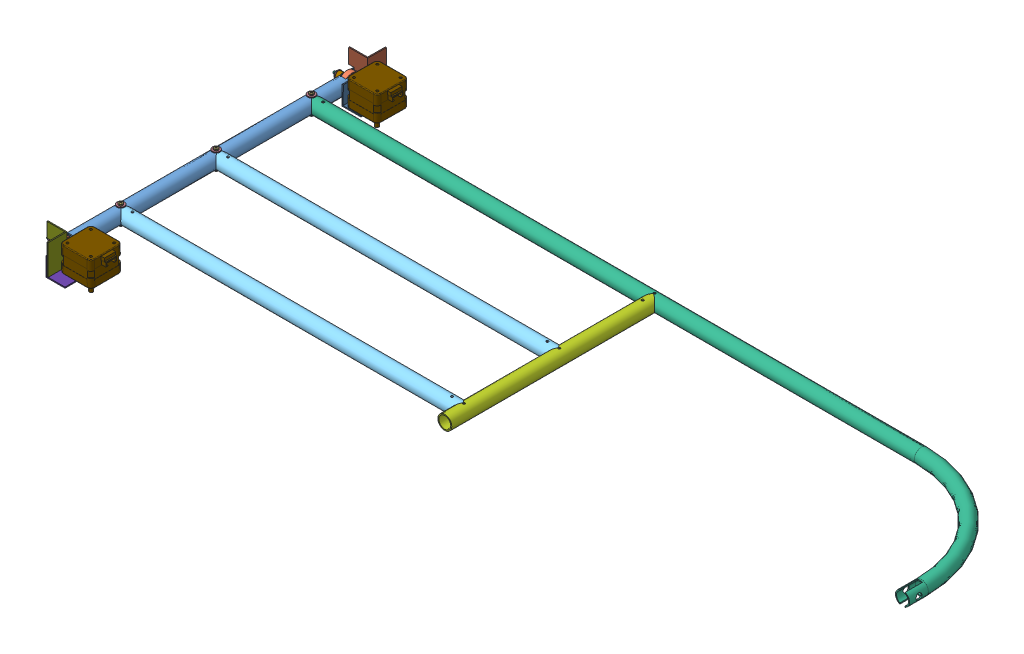
SolidWorks assembly planb, configuration Default. Lengths in mm.
Overall size (995.09 62.65 450.66).
49 component instances, 18 part files, 101 mates.
Components (placement in the parent):
- fr_0001-1: fr_0001 [Default] at (6.245 11.5979 -203.2) size (18.72 18.72 406.4)
- bearing_0006-1: bearing_0006 [Default] at (9.7384 11.5979 190.5) x (0 0.62992 0.77666) z (-1 0 0) size (22 22 7.01)
- bearing_0006-2: bearing_0006 [Default] at (9.6944 11.5979 -190.5) x (0 -0.257155 0.96637) z (-1 0 0) size (22 22 7.01)
- fr_0006-1: fr_0006 [Default] at (6.245 11.5979 127) x (-1 0 0) z (0 0 -1) size (15.98 15.98 25.4)
- fr_0006-2: fr_0006 [Default] at (6.245 11.5979 -25.4) size (15.98 15.98 25.4)
- fr_0006-3: fr_0006 [Default] at (6.245 11.5979 -152.4) size (15.98 15.98 25.4)
- fr_0007-1: fr_0007 [Default] at (2.92 11.5979 114.3) x (0 0 -1) z (1 0 0) size (15.85 15.85 25.4)
- fr_0007-2: fr_0007 [Default] at (2.92 11.5979 -12.7) x (0 0 -1) z (1 0 0) size (15.85 15.85 25.4)
- fr_0007-3: fr_0007 [Default] at (2.92 11.5979 -139.7) x (0 0 -1) z (1 0 0) size (15.85 15.85 25.4)
- fr_0002-1: fr_0002 [Default] at (463.3 11.5979 114.3) x (0 0 -1) z (-1 0 0) size (18.72 18.72 455.37)
- fr_0002-2: fr_0002 [Default] at (6.09 11.5979 -12.7) x (0 0 -1) z (1 0 0) size (18.72 18.72 455.37)
- fr_0003-1: fr_0003 [Default] at (6.09 11.5979 -139.7) x (0 0 1) z (1 0 0) size (186.76 18.72 973.3)
- fr_0004-1: fr_0004 [Default] at (463.145 11.5979 -139.7) size (18.72 18.72 278.48)
- fr_0006-4: fr_0006 [Default] at (463.145 11.5979 101.6) size (15.98 15.98 25.4)
- fr_0006-5: fr_0006 [Default] at (463.145 11.5979 -25.4) size (15.98 15.98 25.4)
- fr_0006-6: fr_0006 [Default] at (450.445 11.5979 -139.7) x (0 0 1) z (1 0 0) size (15.98 15.98 25.4)
- fr_0007-4: fr_0007 [Default] at (466.47 11.5979 114.3) x (0 0 1) z (-1 0 0) size (15.85 15.85 25.4)
- fr_0007-5: fr_0007 [Default] at (466.47 11.5979 -12.7) x (0 0 1) z (-1 0 0) size (15.85 15.85 25.4)
- fr_0007-6: fr_0007 [Default] at (463.145 11.5979 -143.025) size (15.85 15.85 25.4)
- fr_0008-1: fr_0008 [Default] at (17.685 11.5979 -190.5) x (0 0.959946 -0.280186) z (-1 0 0) size (9.4 9.4 26)
- fr_0009-1: fr_0009 [Default] at (-8.315 11.5979 -190.5) x (0 0 -1) z (1 0 0) size (9.4 9.4 5)
- fr_0010-1: fr_0010 [Default] at (17.685 23.8614 -225.2243) x (1 0 0) z (0 0.009997 0.99995) size (25.22 25.22 56)
- fr_0011-1: fr_0011 [Default] at (20.525 40.0606 -225.3863) x (-1 0 0) z (0 -0.99995 0.009997) size (25.22 25.22 40)
- B18.6.7M - M3 x 0.5 x 25 Type I Cross Recessed PHMS --25N-1: B18.6.7M - M3 x 0.5 x 25 Type I Cross Recessed PHMS --25N [Default] at (6.245 24.5579 114.3) x (0 -1 0) z (0 0 1) size (27.37 5.6 5.6)
- B18.22M - Plain washer, 3 mm, regular-1: B18.22M - Plain washer, 3 mm, regular [Default] at (6.245 2.2379 114.3) x (0 1 0) z (0 0 1) size (1.2 10 10)
- B18.22M - Plain washer, 3 mm, regular-2: B18.22M - Plain washer, 3 mm, regular [Default] at (6.245 20.9579 114.3) x (0 -1 0) z (0 0 1) size (1.2 10 10)
- B18.2.4.1M - Hex nut, Style 1,  M3 x 0.5 --D-N-1: B18.2.4.1M - Hex nut, Style 1,  M3 x 0.5 --D-N [Default] at (6.245 -1.3621 114.3) x (1 0 0) z (0 -1 0) size (5.5 6.35 2.4)
- B18.6.7M - M3 x 0.5 x 25 Type I Cross Recessed PHMS --25N-2: B18.6.7M - M3 x 0.5 x 25 Type I Cross Recessed PHMS --25N [Default] at (6.245 24.5579 -12.7) x (0 -1 0) z (0 0 1) size (27.37 5.6 5.6)
- B18.6.7M - M3 x 0.5 x 25 Type I Cross Recessed PHMS --25N-3: B18.6.7M - M3 x 0.5 x 25 Type I Cross Recessed PHMS --25N [Default] at (6.245 24.5579 -139.7) x (0 -1 0) z (0 0 1) size (27.37 5.6 5.6)
- B18.22M - Plain washer, 3 mm, regular-3: B18.22M - Plain washer, 3 mm, regular [Default] at (6.245 20.9579 -139.7) x (0 -1 0) z (0 0 1) size (1.2 10 10)
- B18.22M - Plain washer, 3 mm, regular-4: B18.22M - Plain washer, 3 mm, regular [Default] at (19.105 11.5979 -190.5) x (-1 0 0) z (0 0 1) size (1.2 10 10)
- B18.2.4.1M - Hex nut, Style 1,  M3 x 0.5 --D-N-2: B18.2.4.1M - Hex nut, Style 1,  M3 x 0.5 --D-N [Default] at (6.245 -1.3621 -139.7) x (1 0 0) z (0 -1 0) size (5.5 6.35 2.4)
- B18.2.4.1M - Hex nut, Style 1,  M3 x 0.5 --D-N-3: B18.2.4.1M - Hex nut, Style 1,  M3 x 0.5 --D-N [Default] at (6.245 -1.3621 -12.7) x (1 0 0) z (0 -1 0) size (5.5 6.35 2.4)
- B18.6.7M - M3 x 0.5 x 35 Type I Cross Recessed PHMS --35N-1: B18.6.7M - M3 x 0.5 x 35 Type I Cross Recessed PHMS --35N [Default] at (22.705 11.5979 -190.5) x (-1 0 0) z (0 0 1) size (37.37 5.6 5.6)
- B18.22M - Plain washer, 3 mm, regular-5: B18.22M - Plain washer, 3 mm, regular [Default] at (6.245 20.9579 -12.7) x (0 -1 0) z (0 0 1) size (1.2 10 10)
- B18.2.4.1M - Hex nut, Style 1,  M3 x 0.5 --D-N-4: B18.2.4.1M - Hex nut, Style 1,  M3 x 0.5 --D-N [Default] at (-9.515 11.5979 -190.5) x (0 0.99994 0.010936) z (1 0 0) size (5.5 6.35 2.4)
- B18.22M - Plain washer, 3 mm, regular-6: B18.22M - Plain washer, 3 mm, regular [Default] at (6.245 2.2379 -139.7) x (0 1 0) z (0 0 1) size (1.2 10 10)
- B18.22M - Plain washer, 3 mm, regular-7: B18.22M - Plain washer, 3 mm, regular [Default] at (-8.315 11.5979 -190.5) size (1.2 10 10)
- B18.22M - Plain washer, 3 mm, regular-8: B18.22M - Plain washer, 3 mm, regular [Default] at (6.245 2.2379 -12.7) x (0 1 0) z (0 0 1) size (1.2 10 10)
- fr_0014-1: fr_0014 [Default] at (20.445 0.1994 225.0319) x (-1 0 0) z (0 0.999982 0.006033) size (25.22 25.22 40)
- fr_0012-1: fr_0012 [Default] at (17.605 24.3368 169.1765) x (1 0 0) z (0 -0.006033 0.999982) size (25.22 25.22 56)
- fr_0008-2: fr_0008 [Default] at (17.605 11.5979 190.5) x (0 0.963539 -0.267568) z (-1 0 0) size (9.4 9.4 26)
- fr_0009-2: fr_0009 [Default] at (-8.395 11.5979 190.5) x (0 -0.963539 0.267568) z (1 0 0) size (9.4 9.4 5)
- B18.6.7M - M3 x 0.5 x 35 Type I Cross Recessed PHMS --35N-2: B18.6.7M - M3 x 0.5 x 35 Type I Cross Recessed PHMS --35N [Default] at (22.625 11.5979 190.5) x (-1 0 0) z (0 0.963539 -0.267568) size (37.37 5.6 5.6)
- B18.2.4.1M - Hex nut, Style 1,  M3 x 0.5 --D-N-5: B18.2.4.1M - Hex nut, Style 1,  M3 x 0.5 --D-N [Default] at (-9.595 11.5979 190.5) x (0 0.963539 -0.267568) z (1 0 0) size (5.5 6.35 2.4)
- B18.22M - Plain washer, 3 mm, regular-9: B18.22M - Plain washer, 3 mm, regular [Default] at (-9.595 11.5979 190.5) x (-1 0 0) z (0 0.963539 -0.267568) size (1.2 10 10)
- B18.22M - Plain washer, 3 mm, regular-10: B18.22M - Plain washer, 3 mm, regular [Default] at (19.025 11.5979 190.5) x (-1 0 0) z (0 0.963539 -0.267568) size (1.2 10 10)
- SW3dPS-037-1: SW3dPS-037 [Default] at (42.825 0.4081 190.4325) x (0 0.999982 0.006033) z (0 -0.006033 0.999982) size (56.01 48 42)
- SW3dPS-037-2: SW3dPS-037 [Default] at (42.905 0.4085 -190.3881) x (0 0.99995 -0.009997) z (0 0.009997 0.99995) size (56.01 48 42)
Mates (geometry in assembly coordinates):
- Concentric2: concentric aligned: cylinder of fr_0001-1 through (6.245 11.5979 203.2) axis (0 0 -1) radius 9.36; circle of fr_0006-1
- Concentric5: concentric aligned: cylinder of fr_0001-1 through (15.605 11.5979 114.3) axis (-1 0 0) radius 3.5; cylinder of fr_0006-1 through (14.235 11.5979 114.3) axis (-1 0 0) radius 3.5
- Concentric6: concentric anti-aligned: cylinder of fr_0001-1 through (6.245 11.5979 203.2) axis (0 0 -1) radius 9.36; circle of fr_0006-2
- Concentric7: concentric anti-aligned: cylinder of fr_0001-1 through (15.605 11.5979 -12.7) axis (-1 0 0) radius 3.5; cylinder of fr_0006-2 through (-1.745 11.5979 -12.7) axis (1 0 0) radius 3.5
- Concentric8: concentric anti-aligned: cylinder of fr_0001-1 through (6.245 11.5979 203.2) axis (0 0 -1) radius 9.36; circle of fr_0006-3
- Concentric9: concentric anti-aligned: cylinder of fr_0001-1 through (15.605 11.5979 -139.7) axis (-1 0 0) radius 3.5; cylinder of fr_0006-3 through (-1.745 11.5979 -139.7) axis (1 0 0) radius 3.5
- Concentric11: concentric aligned: cylinder of fr_0006-1 through (14.235 11.5979 114.3) axis (-1 0 0) radius 3.5; cylinder of fr_0007-1 through (15.67 11.5979 114.3) axis (-1 0 0) radius 3.48
- Concentric12: concentric aligned: cylinder of fr_0006-1 through (6.245 3.6079 114.3) axis (0 1 0) radius 1.55; cylinder of fr_0007-1 through (6.245 3.6729 114.3) axis (0 1 0) radius 1.55
- Concentric13: concentric anti-aligned: cylinder of fr_0006-2 through (-1.745 11.5979 -12.7) axis (1 0 0) radius 3.5; cylinder of fr_0007-2 through (15.67 11.5979 -12.7) axis (-1 0 0) radius 3.48
- Concentric14: concentric aligned: cylinder of fr_0006-2 through (6.245 3.6079 -12.7) axis (0 1 0) radius 1.55; cylinder of fr_0007-2 through (6.245 3.6729 -12.7) axis (0 1 0) radius 1.55
- Concentric15: concentric anti-aligned: cylinder of fr_0006-3 through (-1.745 11.5979 -139.7) axis (1 0 0) radius 3.5; cylinder of fr_0007-3 through (15.67 11.5979 -139.7) axis (-1 0 0) radius 3.48
- Concentric16: concentric aligned: cylinder of fr_0006-3 through (6.245 3.6079 -139.7) axis (0 1 0) radius 1.55; cylinder of fr_0007-3 through (6.245 3.6729 -139.7) axis (0 1 0) radius 1.55
- Concentric17: concentric aligned: cylinder of fr_0001-1 through (15.605 11.5979 -190.5) axis (-1 0 0) radius 4; cylinder of bearing_0006-2 through (-9.3056 11.5979 -190.5) axis (-1 0 0) radius 4
- Concentric18: concentric anti-aligned: cylinder of fr_0001-1 through (-3.115 11.5979 190.5) axis (1 0 0) radius 4; cylinder of bearing_0006-1 through (-9.2616 11.5979 190.5) axis (-1 0 0) radius 4
- Concentric19: concentric anti-aligned: cylinder of fr_0007-1 through (28.32 11.5979 114.3) axis (-1 0 0) radius 7.925; cylinder of fr_0002-1 through (6.1 11.5979 114.3) axis (1 0 0) radius 9.36
- Parallel1: parallel anti-aligned: cylinder of fr_0007-1 through (21.97 3.6729 114.3) axis (0 1 0) radius 1.55; cylinder of fr_0002-1 through (21.97 20.9579 114.3) axis (0 -1 0) radius 1.55
- Concentric20: concentric anti-aligned: cylinder of fr_0007-1 through (21.97 3.6729 114.3) axis (0 1 0) radius 1.55; cylinder of fr_0002-1 through (21.97 20.9579 114.3) axis (0 -1 0) radius 1.55
- Concentric21: concentric aligned: cylinder of fr_0007-2 through (28.32 11.5979 -12.7) axis (-1 0 0) radius 7.925; cylinder of fr_0002-2 through (463.29 11.5979 -12.7) axis (-1 0 0) radius 9.36
- Concentric22: concentric aligned: cylinder of fr_0007-2 through (21.97 3.6729 -12.7) axis (0 1 0) radius 1.55; cylinder of fr_0002-2 through (21.97 2.2379 -12.7) axis (0 1 0) radius 1.55
- Concentric23: concentric aligned: cylinder of fr_0007-3 through (28.32 11.5979 -139.7) axis (-1 0 0) radius 7.925; cylinder of fr_0003-1 through (818.29 11.5979 -139.7) axis (-1 0 0) radius 7.99
- Concentric24: concentric anti-aligned: cylinder of fr_0007-3 through (21.97 3.6729 -139.7) axis (0 1 0) radius 1.55; cylinder of fr_0003-1 through (21.97 20.9579 -139.7) axis (0 -1 0) radius 1.55
- Concentric25: concentric anti-aligned: cylinder of fr_0002-1 through (6.1 11.5979 114.3) axis (1 0 0) radius 7.99; circle of fr_0007-4
- Concentric26: concentric anti-aligned: cylinder of fr_0002-1 through (447.42 20.9579 114.3) axis (0 -1 0) radius 1.55; cylinder of fr_0007-4 through (447.42 3.6729 114.3) axis (0 1 0) radius 1.55
- Concentric27: concentric anti-aligned: cylinder of fr_0002-2 through (463.29 11.5979 -12.7) axis (-1 0 0) radius 7.99; cylinder of fr_0007-5 through (441.07 11.5979 -12.7) axis (1 0 0) radius 7.925
- Concentric28: concentric aligned: cylinder of fr_0002-2 through (447.42 2.2379 -12.7) axis (0 1 0) radius 1.55; cylinder of fr_0007-5 through (447.42 3.6729 -12.7) axis (0 1 0) radius 1.55
- Concentric29: concentric anti-aligned: cylinder of fr_0004-1 through (463.145 11.5979 139.7) axis (0 0 -1) radius 7.99; circle of fr_0006-5
- Concentric30: concentric aligned: cylinder of fr_0004-1 through (453.785 11.5979 -12.7) axis (1 0 0) radius 3.5; cylinder of fr_0006-5 through (455.155 11.5979 -12.7) axis (1 0 0) radius 3.5
- Concentric31: concentric anti-aligned: cylinder of fr_0004-1 through (463.145 11.5979 139.7) axis (0 0 -1) radius 7.99; circle of fr_0006-4
- Concentric32: concentric aligned: cylinder of fr_0004-1 through (463.145 2.2379 114.3) axis (0 1 0) radius 1.55; cylinder of fr_0006-4 through (463.145 3.6079 114.3) axis (0 1 0) radius 1.55
- Concentric33: concentric aligned: cylinder of fr_0004-1 through (463.145 11.5979 139.7) axis (0 0 -1) radius 7.99; cylinder of fr_0007-6 through (463.145 11.5979 -117.625) axis (0 0 -1) radius 7.925
- Concentric35: concentric anti-aligned: cylinder of fr_0006-4 through (455.155 11.5979 114.3) axis (1 0 0) radius 3.5; circle of fr_0007-4
- Concentric39: concentric aligned: cylinder of fr_0006-5 through (463.145 3.6079 -12.7) axis (0 1 0) radius 1.55; cylinder of fr_0007-5 through (463.145 3.6729 -12.7) axis (0 1 0) radius 1.55
- Concentric40: concentric anti-aligned: cylinder of fr_0003-1 through (818.29 11.5979 -139.7) axis (-1 0 0) radius 7.99; circle of fr_0006-6
- Concentric41: concentric aligned: cylinder of fr_0003-1 through (463.145 20.9579 -139.7) axis (0 -1 0) radius 1.55; cylinder of fr_0006-6 through (463.145 19.5879 -139.7) axis (0 -1 0) radius 1.55
- Concentric43: concentric anti-aligned: cylinder of fr_0006-6 through (463.145 19.5879 -139.7) axis (0 -1 0) radius 1.55; cylinder of fr_0007-6 through (463.145 3.6729 -139.7) axis (0 1 0) radius 1.55
- Concentric563: concentric anti-aligned: cylinder of fr_0008-1 through (-8.315 11.5979 -190.5) axis (1 0 0) radius 1.5; cylinder of fr_0010-1 through (42.905 11.5979 -190.5) axis (-1 0 0) radius 1.5
- Coincident42: coincident anti-aligned: plane of fr_0008-1 through (17.685 11.5979 -190.5) normal (1 0 0); plane of fr_0010-1 through (17.685 24.4212 -169.2271) normal (-1 0 0)
- Coincident46: coincident aligned: plane of fr_0010-1 through (17.685 23.8614 -225.2243) normal (0 -0.009997 -0.99995); plane of fr_0011-1 through (19.105 0.0626 -224.9864) normal (0 -0.009997 -0.99995)
- Coincident47: coincident anti-aligned: plane of fr_0010-1 through (19.105 24.4212 -169.2271) normal (1 0 0); plane of fr_0011-1 through (19.105 0.0626 -224.9864) normal (-1 0 0)
- Coincident49: coincident anti-aligned: plane of fr_0010-1 through (42.905 0.6224 -168.9892) normal (0 0.99995 -0.009997); plane of fr_0011-1 through (20.525 0.0626 -224.9864) normal (0 -0.99995 0.009997)
- Concentric565: concentric anti-aligned: cylinder of fr_0001-1 through (15.605 11.5979 -190.5) axis (-1 0 0) radius 4; cylinder of fr_0008-1 through (-8.315 11.5979 -190.5) axis (1 0 0) radius 3
- Concentric566: concentric anti-aligned: cylinder of fr_0008-1 through (-8.315 11.5979 -190.5) axis (1 0 0) radius 3; cylinder of fr_0009-1 through (-3.315 11.5979 -190.5) axis (-1 0 0) radius 3
- Coincident50: coincident anti-aligned: plane of fr_0008-1 through (-3.315 11.5979 -190.5) normal (-1 0 0); plane of fr_0009-1 through (-3.315 11.5979 -190.5) normal (1 0 0)
- Concentric596: concentric aligned: cylinder of B18.6.7M - M3 x 0.5 x 25 Type I Cross Recessed PHMS --25N-1 through (6.245 49.9579 114.3) axis (0 1 0) radius 1.5; cylinder of B18.22M - Plain washer, 3 mm, regular-2 through (6.245 55.8829 114.3) axis (0 1 0) radius 1.84
- Coincident69: coincident anti-aligned: plane of B18.6.7M - M3 x 0.5 x 25 Type I Cross Recessed PHMS --25N-1 through (7.745 22.1579 114.3) normal (0 -1 0); plane of B18.22M - Plain washer, 3 mm, regular-2 through (11.245 22.1579 114.3) normal (0 1 0)
- Concentric597: concentric aligned: cylinder of fr_0001-1 through (6.245 2.2379 114.3) axis (0 1 0) radius 1.55; cylinder of B18.6.7M - M3 x 0.5 x 25 Type I Cross Recessed PHMS --25N-1 through (6.245 49.9579 114.3) axis (0 1 0) radius 1.5
- Tangent3: tangent anti-aligned: cylinder of fr_0001-1 through (6.245 11.5979 203.2) axis (0 0 -1) radius 9.36; plane of B18.22M - Plain washer, 3 mm, regular-2 through (8.085 20.9579 114.3) normal (0 -1 0)
- Concentric598: concentric anti-aligned: cylinder of B18.6.7M - M3 x 0.5 x 25 Type I Cross Recessed PHMS --25N-1 through (6.245 49.9579 114.3) axis (0 1 0) radius 1.5; cylinder of B18.22M - Plain washer, 3 mm, regular-1 through (6.245 -32.6871 114.3) axis (0 -1 0) radius 1.84
- Tangent4: tangent anti-aligned: cylinder of fr_0001-1 through (6.245 11.5979 203.2) axis (0 0 -1) radius 9.36; plane of B18.22M - Plain washer, 3 mm, regular-1 through (4.405 2.2379 114.3) normal (0 1 0)
- Concentric599: concentric anti-aligned: cylinder of B18.6.7M - M3 x 0.5 x 25 Type I Cross Recessed PHMS --25N-1 through (6.245 49.9579 114.3) axis (0 1 0) radius 1.5; cylinder of B18.2.4.1M - Hex nut, Style 1,  M3 x 0.5 --D-N-1 through (6.245 1.0379 114.3) axis (0 -1 0) radius 1.25
- Coincident70: coincident anti-aligned: plane of B18.22M - Plain washer, 3 mm, regular-1 through (1.245 1.0379 114.3) normal (0 -1 0); plane of B18.2.4.1M - Hex nut, Style 1,  M3 x 0.5 --D-N-1 through (6.245 1.0379 117.4754) normal (0 1 0)
- Concentric600: concentric aligned: cylinder of B18.6.7M - M3 x 0.5 x 25 Type I Cross Recessed PHMS --25N-2 through (6.245 49.9579 -12.7) axis (0 1 0) radius 1.5; cylinder of B18.22M - Plain washer, 3 mm, regular-5 through (6.245 55.8829 -12.7) axis (0 1 0) radius 1.84
- Concentric601: concentric aligned: cylinder of B18.6.7M - M3 x 0.5 x 25 Type I Cross Recessed PHMS --25N-3 through (6.245 49.9579 -139.7) axis (0 1 0) radius 1.5; cylinder of B18.22M - Plain washer, 3 mm, regular-3 through (6.245 55.8829 -139.7) axis (0 1 0) radius 1.84
- Concentric602: concentric aligned: cylinder of B18.22M - Plain washer, 3 mm, regular-4 through (54.03 11.5979 -190.5) axis (1 0 0) radius 1.84; cylinder of B18.6.7M - M3 x 0.5 x 35 Type I Cross Recessed PHMS --35N-1 through (48.105 11.5979 -190.5) axis (1 0 0) radius 1.5
- Coincident71: coincident anti-aligned: plane of B18.22M - Plain washer, 3 mm, regular-4 through (20.305 6.5979 -190.5) normal (1 0 0); plane of B18.6.7M - M3 x 0.5 x 35 Type I Cross Recessed PHMS --35N-1 through (20.305 10.0979 -190.5) normal (-1 0 0)
- Coincident72: coincident anti-aligned: plane of B18.6.7M - M3 x 0.5 x 25 Type I Cross Recessed PHMS --25N-3 through (7.745 22.1579 -139.7) normal (0 -1 0); plane of B18.22M - Plain washer, 3 mm, regular-3 through (11.245 22.1579 -139.7) normal (0 1 0)
- Coincident73: coincident anti-aligned: plane of B18.6.7M - M3 x 0.5 x 25 Type I Cross Recessed PHMS --25N-2 through (7.745 22.1579 -12.7) normal (0 -1 0); plane of B18.22M - Plain washer, 3 mm, regular-5 through (11.245 22.1579 -12.7) normal (0 1 0)
- Concentric603: concentric aligned: cylinder of fr_0001-1 through (6.245 2.2379 -12.7) axis (0 1 0) radius 1.55; cylinder of B18.6.7M - M3 x 0.5 x 25 Type I Cross Recessed PHMS --25N-2 through (6.245 49.9579 -12.7) axis (0 1 0) radius 1.5
- Concentric604: concentric aligned: cylinder of fr_0001-1 through (6.245 2.2379 -139.7) axis (0 1 0) radius 1.55; cylinder of B18.6.7M - M3 x 0.5 x 25 Type I Cross Recessed PHMS --25N-3 through (6.245 49.9579 -139.7) axis (0 1 0) radius 1.5
- Tangent6: tangent anti-aligned: cylinder of fr_0001-1 through (6.245 11.5979 203.2) axis (0 0 -1) radius 9.36; plane of B18.22M - Plain washer, 3 mm, regular-5 through (8.085 20.9579 -12.7) normal (0 -1 0)
- Tangent7: tangent anti-aligned: cylinder of fr_0001-1 through (6.245 11.5979 203.2) axis (0 0 -1) radius 9.36; plane of B18.22M - Plain washer, 3 mm, regular-3 through (8.085 20.9579 -139.7) normal (0 -1 0)
- Concentric605: concentric anti-aligned: cylinder of B18.6.7M - M3 x 0.5 x 25 Type I Cross Recessed PHMS --25N-2 through (6.245 49.9579 -12.7) axis (0 1 0) radius 1.5; circle of B18.22M - Plain washer, 3 mm, regular-8
- Concentric606: concentric anti-aligned: cylinder of B18.6.7M - M3 x 0.5 x 25 Type I Cross Recessed PHMS --25N-3 through (6.245 49.9579 -139.7) axis (0 1 0) radius 1.5; cylinder of B18.22M - Plain washer, 3 mm, regular-6 through (6.245 -32.6871 -139.7) axis (0 -1 0) radius 1.84
- Tangent8: tangent anti-aligned: cylinder of fr_0001-1 through (6.245 11.5979 203.2) axis (0 0 -1) radius 9.36; plane of B18.22M - Plain washer, 3 mm, regular-6 through (4.405 2.2379 -139.7) normal (0 1 0)
- Tangent9: tangent anti-aligned: cylinder of fr_0001-1 through (6.245 11.5979 203.2) axis (0 0 -1) radius 9.36; plane of B18.22M - Plain washer, 3 mm, regular-8 through (4.405 2.2379 -12.7) normal (0 1 0)
- Concentric607: concentric anti-aligned: cylinder of B18.6.7M - M3 x 0.5 x 25 Type I Cross Recessed PHMS --25N-2 through (6.245 49.9579 -12.7) axis (0 1 0) radius 1.5; cylinder of B18.2.4.1M - Hex nut, Style 1,  M3 x 0.5 --D-N-3 through (6.245 1.0379 -12.7) axis (0 -1 0) radius 1.25
- Coincident74: coincident anti-aligned: plane of B18.2.4.1M - Hex nut, Style 1,  M3 x 0.5 --D-N-3 through (6.245 1.0379 -9.5246) normal (0 1 0); plane of B18.22M - Plain washer, 3 mm, regular-8 through (1.245 1.0379 -12.7) normal (0 -1 0)
- Concentric608: concentric anti-aligned: cylinder of B18.6.7M - M3 x 0.5 x 25 Type I Cross Recessed PHMS --25N-3 through (6.245 49.9579 -139.7) axis (0 1 0) radius 1.5; cylinder of B18.2.4.1M - Hex nut, Style 1,  M3 x 0.5 --D-N-2 through (6.245 1.0379 -139.7) axis (0 -1 0) radius 1.25
- Coincident75: coincident anti-aligned: plane of B18.2.4.1M - Hex nut, Style 1,  M3 x 0.5 --D-N-2 through (6.245 1.0379 -136.5246) normal (0 1 0); plane of B18.22M - Plain washer, 3 mm, regular-6 through (1.245 1.0379 -139.7) normal (0 -1 0)
- Concentric609: concentric anti-aligned: cylinder of fr_0010-1 through (42.905 11.5979 -190.5) axis (-1 0 0) radius 1.5; cylinder of B18.6.7M - M3 x 0.5 x 35 Type I Cross Recessed PHMS --35N-1 through (48.105 11.5979 -190.5) axis (1 0 0) radius 1.5
- Coincident76: coincident anti-aligned: plane of fr_0010-1 through (19.105 24.4212 -169.2271) normal (1 0 0); plane of B18.22M - Plain washer, 3 mm, regular-4 through (19.105 9.7579 -190.5) normal (-1 0 0)
- Concentric610: concentric anti-aligned: cylinder of B18.6.7M - M3 x 0.5 x 35 Type I Cross Recessed PHMS --35N-1 through (48.105 11.5979 -190.5) axis (1 0 0) radius 1.5; cylinder of B18.22M - Plain washer, 3 mm, regular-7 through (-43.24 11.5979 -190.5) axis (-1 0 0) radius 1.84
- Coincident78: coincident anti-aligned: plane of fr_0008-1 through (-8.315 11.5979 -190.5) normal (-1 0 0); plane of B18.22M - Plain washer, 3 mm, regular-7 through (-8.315 13.4379 -190.5) normal (1 0 0)
- Concentric611: concentric aligned: cylinder of B18.6.7M - M3 x 0.5 x 35 Type I Cross Recessed PHMS --35N-1 through (48.105 11.5979 -190.5) axis (1 0 0) radius 1.5; cylinder of B18.2.4.1M - Hex nut, Style 1,  M3 x 0.5 --D-N-4 through (-11.915 11.5979 -190.5) axis (1 0 0) radius 1.25
- Coincident80: coincident anti-aligned: plane of fr_0001-1 through (2.675 2.2379 -203.2) normal (1 0 0); plane of fr_0011-1 through (2.675 18.3138 -199.9476) normal (-1 0 0)
- Coincident81: coincident anti-aligned: plane of B18.2.4.1M - Hex nut, Style 1,  M3 x 0.5 --D-N-4 through (-9.515 11.5632 -187.3248) normal (1 0 0); plane of B18.22M - Plain washer, 3 mm, regular-7 through (-9.515 16.5979 -190.5) normal (-1 0 0)
- Concentric612: concentric anti-aligned: cylinder of fr_0001-1 through (-3.115 11.5979 190.5) axis (1 0 0) radius 4; circle of fr_0008-2
- Tangent10: tangent anti-aligned: cylinder of fr_0001-1 through (6.245 11.5979 203.2) axis (0 0 -1) radius 9.36; plane of fr_0008-2 through (15.605 11.5979 190.5) normal (-1 0 0)
- Concentric613: concentric aligned: circle of fr_0008-2; circle of fr_0009-2
- Coincident83: coincident anti-aligned: plane of fr_0008-2 through (-3.395 11.5979 190.5) normal (-1 0 0); plane of fr_0009-2 through (-3.395 11.5979 190.5) normal (1 0 0)
- Coincident84: coincident aligned: plane of fr_0014-1 through (19.025 40.1987 225.2732) normal (0 -0.006033 0.999982); plane of fr_0012-1 through (17.605 23.999 225.1754) normal (0 -0.006033 0.999982)
- Coincident85: coincident anti-aligned: plane of fr_0014-1 through (19.025 40.1987 225.2732) normal (-1 0 0); plane of fr_0012-1 through (19.025 23.999 225.1754) normal (1 0 0)
- Coincident86: coincident anti-aligned: plane of fr_0014-1 through (20.445 0.1994 225.0319) normal (0 -0.999982 -0.006033); plane of fr_0012-1 through (42.825 0.1994 225.0319) normal (0 0.999982 0.006033)
- Concentric614: concentric anti-aligned: circle of fr_0012-1; circle of fr_0008-2
- Coincident87: coincident anti-aligned: plane of fr_0012-1 through (17.605 23.999 225.1754) normal (-1 0 0); plane of fr_0008-2 through (17.605 11.5979 190.5) normal (1 0 0)
- Concentric615: concentric aligned: circle of B18.6.7M - M3 x 0.5 x 35 Type I Cross Recessed PHMS --35N-2; circle of B18.22M - Plain washer, 3 mm, regular-10
- Concentric616: concentric anti-aligned: circle of fr_0012-1; circle of B18.22M - Plain washer, 3 mm, regular-10
- Coincident88: coincident anti-aligned: plane of fr_0012-1 through (19.025 23.999 225.1754) normal (1 0 0); plane of B18.22M - Plain washer, 3 mm, regular-10 through (19.025 12.0903 192.2729) normal (-1 0 0)
- Coincident89: coincident anti-aligned: plane of B18.6.7M - M3 x 0.5 x 35 Type I Cross Recessed PHMS --35N-2 through (20.225 11.9993 191.9453) normal (-1 0 0); plane of B18.22M - Plain washer, 3 mm, regular-10 through (20.225 12.9358 195.3177) normal (1 0 0)
- Concentric617: concentric aligned: circle of B18.6.7M - M3 x 0.5 x 35 Type I Cross Recessed PHMS --35N-2; circle of B18.22M - Plain washer, 3 mm, regular-9
- Coincident90: coincident anti-aligned: plane of fr_0009-2 through (-8.395 11.5979 190.5) normal (-1 0 0); plane of B18.22M - Plain washer, 3 mm, regular-9 through (-8.395 12.9358 195.3177) normal (1 0 0)
- Concentric618: concentric aligned: circle of B18.6.7M - M3 x 0.5 x 35 Type I Cross Recessed PHMS --35N-2; circle of B18.2.4.1M - Hex nut, Style 1,  M3 x 0.5 --D-N-5
- Coincident91: coincident anti-aligned: plane of B18.2.4.1M - Hex nut, Style 1,  M3 x 0.5 --D-N-5; plane of B18.22M - Plain washer, 3 mm, regular-9 through (-9.595 12.0903 192.2729) normal (-1 0 0)
- Concentric619: concentric anti-aligned: cylinder of fr_0012-1 through (42.825 24.2077 190.5761) axis (0 -0.999982 -0.006033) radius 11; cylinder of SW3dPS-037-1 through (42.825 -1.5918 190.4204) axis (0 0.999982 0.006033) radius 11
- Concentric620: concentric anti-aligned: circle of fr_0010-1; cylinder of SW3dPS-037-2 through (42.905 -1.5914 -190.3681) axis (0 0.99995 -0.009997) radius 11
- Concentric621: concentric anti-aligned: circle of fr_0010-1; circle of SW3dPS-037-2
- Concentric622: concentric anti-aligned: circle of fr_0010-1; circle of SW3dPS-037-2
- Coincident94: coincident anti-aligned: plane of fr_0010-1 through (42.905 0.6224 -168.9892) normal (0 0.99995 -0.009997); plane of SW3dPS-037-2 through (21.905 0.1986 -211.3871) normal (0 -0.99995 0.009997)
- Concentric626: concentric anti-aligned: cylinder of fr_0012-1 through (42.825 24.2077 190.5761) axis (0 -0.999982 -0.006033) radius 11; cylinder of SW3dPS-037-1 through (42.825 -1.5918 190.4204) axis (0 0.999982 0.006033) radius 11
- Concentric627: concentric anti-aligned: circle of fr_0012-1; circle of SW3dPS-037-1
- Coincident96: coincident anti-aligned: plane of fr_0012-1 through (42.825 0.1994 225.0319) normal (0 0.999982 0.006033); plane of SW3dPS-037-1 through (21.825 0.5348 169.4329) normal (0 -0.999982 -0.006033)
